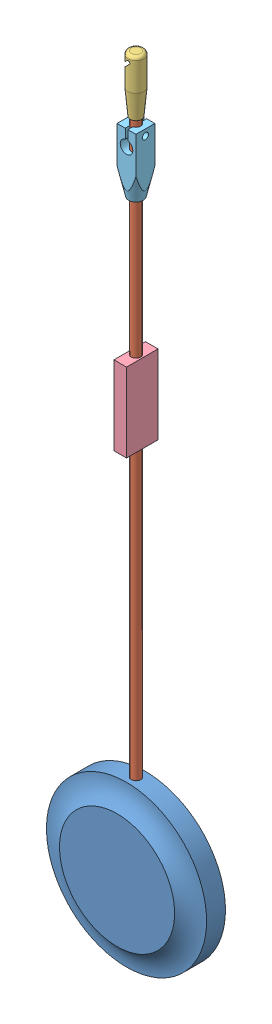
SolidWorks assembly pendulum assy, configuration Default. Lengths in mm.
Overall size (50.8 250.4 12).
7 component instances, 7 part files, 23 mates.
Components (placement in the parent):
- pendulum bob-1: pendulum bob [Default] at origin size (50.8 50.8 12)
- pendulum rod-1: pendulum rod [Default] at (0 15 0) size (3 200 3)
- pendulum hook-1: pendulum hook [Default] at (0 215 0) x (0 0 1) z (-1 0 0) size (5 18 5)
- pendulum block-1: pendulum block [Default] at (0 116.5269 0) x (0 0 1) z (-1 0 0) size (10 25 4)
- pendulum layout-1: pendulum layout [Default] at origin
- crutch top-1: crutch top [Default] at origin size (7.17 20 7.17)
- crutch rod-1: crutch rod [Default] at origin size (2 91.36 22) (hidden)
Mates (geometry in assembly coordinates):
- Concentric63: concentric: cylinder of pendulum bob-1 through (0 25.4 0) axis (0 -1 0) radius 1.5; cylinder of pendulum rod-1 through (0 215 0) axis (0 -1 0) radius 1.5
- Coincident52: coincident: plane of pendulum bob-1 through (0 15 0) normal (0 1 0); plane of pendulum rod-1 through (0 15 0) normal (0 -1 0)
- Coincident53: coincident: plane of pendulum bob-1 through (0 0 0) normal (1 0 0); plane of pendulum rod-1 through (0 15 0) normal (1 0 0)
- Concentric64: concentric: cylinder of pendulum rod-1 through (0 215 0) axis (0 -1 0) radius 1.5; cylinder of pendulum hook-1 through (0 219.2426 0) axis (0 -1 0) radius 1.5
- Coincident54: coincident: plane of pendulum rod-1 through (0 215 0) normal (0 1 0); plane of pendulum hook-1 through (0 215 0) normal (0 -1 0)
- Coincident55: coincident: plane of pendulum bob-1 through (0 0 0) normal (0 0 1); plane of assembly through (0 0 0) normal (0 0 1)
- Coincident56: coincident: plane of pendulum bob-1 through (0 0 0) normal (0 1 0); plane of assembly through (0 0 0) normal (0 1 0)
- Coincident57: coincident: plane of pendulum bob-1 through (0 0 0) normal (1 0 0); plane of assembly through (0 0 0) normal (1 0 0)
- Concentric65: concentric: cylinder of pendulum rod-1 through (0 215 0) axis (0 -1 0) radius 1.5; cylinder of pendulum block-1 through (0 141.5269 0) axis (0 -1 0) radius 1.5
- Coincident58: coincident: plane of pendulum bob-1 through (0 0 0) normal (1 0 0); plane of pendulum block-1 through (0 116.5269 0) normal (-1 0 0)
- Coincident59: coincident: plane of pendulum bob-1 through (0 0 0) normal (1 0 0); plane of pendulum hook-1 through (0 215 0) normal (-1 0 0)
- InPlace1: in place: plane of ? through (0 0 0) normal (0 0 1); moOrthogonalPlaneRef_w of ? through (0 0 0) normal (0 1 0); plane of ? through (0 0 0) normal (1 0 0); unknown of ?
- Coincident60: coincident: plane of pendulum layout-1; plane of assembly
- Coincident61: coincident: plane of ? through (0 0 0) normal (0 1 0)
- Coincident62: coincident: plane of ? through (0 0 0) normal (1 0 0)
- InPlace2: in place: plane of ? through (0 0 0) normal (0 0 1); plane of ? through (0 0 0) normal (0 1 0); plane of ? through (0 0 0) normal (1 0 0); unknown of ?
- Coincident63: coincident: plane of crutch top-1; plane of assembly
- Coincident64: coincident: plane of ? through (0 0 0) normal (0 1 0)
- Coincident65: coincident: plane of ? through (0 0 0) normal (1 0 0)
- InPlace3: in place: plane of ? through (0 0 0) normal (0 0 1); plane of ? through (0 0 0) normal (0 1 0); plane of ? through (0 0 0) normal (1 0 0); unknown of ?
- Coincident66: coincident: plane of crutch rod-1; plane of assembly
- Coincident67: coincident: plane of ? through (0 0 0) normal (0 1 0)
- Coincident68: coincident: plane of ? through (0 0 0) normal (1 0 0)
